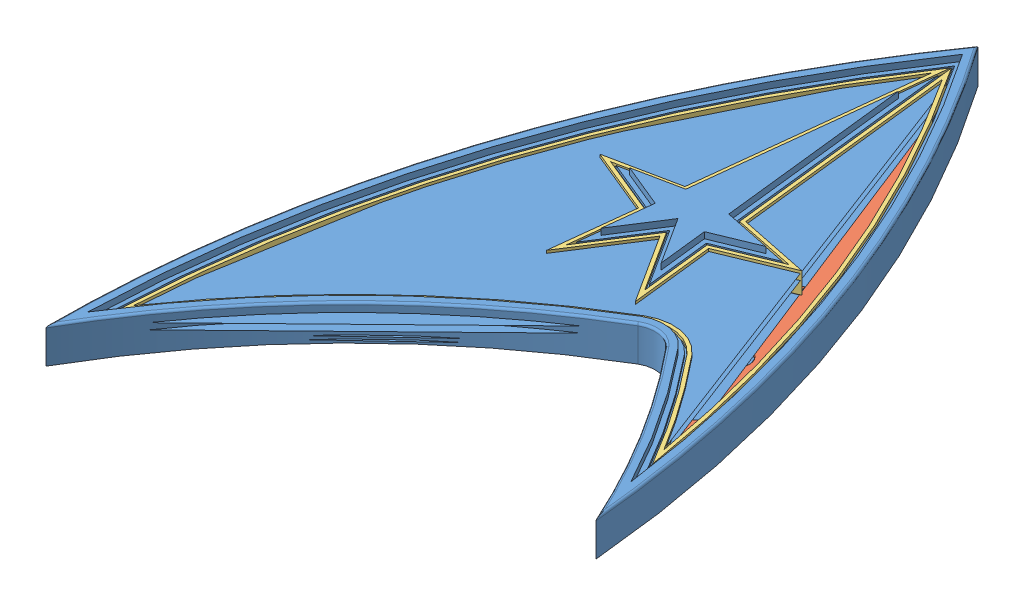
SolidWorks assembly TOS_Badge, configuration Default. Lengths in mm.
Overall size (50.31 4.12 80.45).
3 component instances, 3 part files, 2 mates.
Components (placement in the parent):
- TOS_Badge-2: TOS_Badge [Default] at origin size (50.31 4.12 80.45)
- TOS_LightGuide-3: TOS_LightGuide [Default] at origin size (46.01 0.8 72.18)
- TOS_LightGuide_Side-1: TOS_LightGuide_Side [Default] at (0 0.9 0) size (45.42 2.4 71.06)
Mates (geometry in assembly coordinates):
- Coincident3: coincident: point of TOS_Badge-2
- Coincident5: coincident aligned: plane of TOS_Badge-2 through (0 3.3 0) normal (0 1 0); plane of TOS_LightGuide_Side-1 through (-89.3626 3.3 0) normal (0 1 0)
